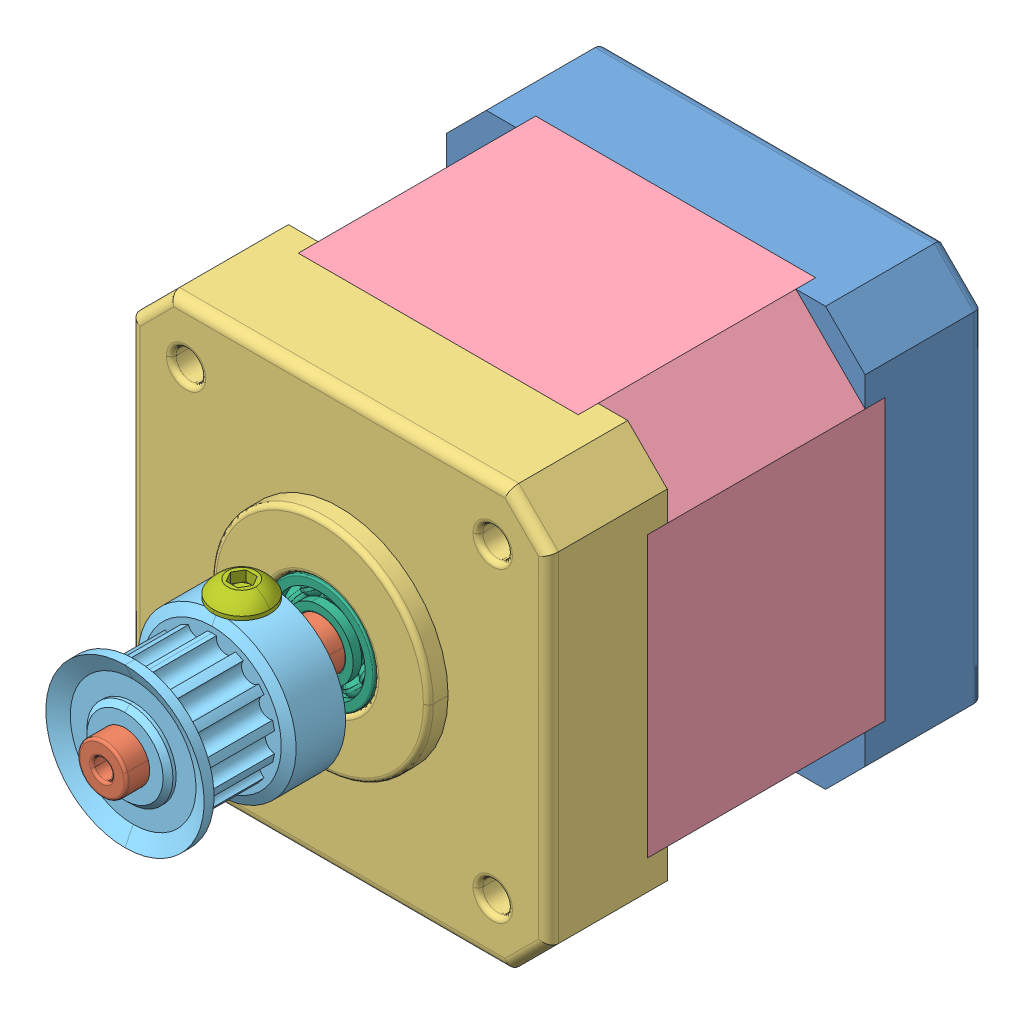
SolidWorks assembly assembly, configuration Default. Lengths in mm.
Overall size (42.3 42.3 68).
13 component instances, 8 part files, 0 mates.
Components (placement in the parent):
- assembly.STEP-1: assembly.STEP [Default] at origin size (42.3 42.3 68)
  - base.STEP-1: base.STEP [Default] at (10.8393 27.1386 29.2882) size (42.3 42.3 12)
  - axial_rod.STEP-1: axial_rod.STEP [Default] at (10.8393 27.1386 29.2882) x (0.938585 0.345048 0) z (0 0 1) size (5 5 68)
  - back_plate.STEP-1: back_plate.STEP [Default] at (10.8393 27.1386 73.2882) x (-1 0 0) z (0 0 -1) size (42.3 42.3 14)
  - body.STEP-1: body.STEP [Default] at (10.8393 27.1386 39.2882) size (42.3 42.3 24)
  - pulley.STEP-1: pulley.STEP [Default] at (10.8393 27.1386 80.1596) x (0 0 1) z (-0.000036 1 0) size (14.8 16 16)
  - instrument ball bearing_68_am_AFBMA 12.1.4.1 - 0050-11 - 10,DE,AC,10_68.STEP-1: instrument ball bearing_68_am_AFBMA 12.1.4.1 - 0050-11 - 10,DE,AC,10_68.STEP [Default] at (10.8393 27.1386 73.7882) x (0 0 1) z (0.245688 -0.969349 0) size (3 11 11)
  - instrument ball bearing_68_am_AFBMA 12.1.4.1 - 0050-11 - 10,DE,AC,10_68.STEP-2: instrument ball bearing_68_am_AFBMA 12.1.4.1 - 0050-11 - 10,DE,AC,10_68.STEP [Default] at (10.8393 27.1386 30.7882) x (0 0 1) z (-0.240367 -0.970682 0) size (3 11 11)
  - socket button head cap screw_am_B18.3.4M - 3 x 0.5 x 5 SBHCS --S.STEP-1: socket button head cap screw_am_B18.3.4M - 3 x 0.5 x 5 SBHCS --S.STEP [Default] at (10.839 36.7886 83.1596) x (0.000036 -1 0) z (0 0 1) size (6.65 5.7 5.7)
  - pan cross head_am_B18.6.7M - M3 x 0.5 x 5 Type I Cross Recessed PHMS --5S.STEP-1: pan cross head_am_B18.6.7M - M3 x 0.5 x 5 Type I Cross Recessed PHMS --5S.STEP [Default] at (26.3393 42.6386 29.8882) x (0 0 1) z (-0.840101 -0.542431 0) size (7.37 5.6 5.6)
  - pan cross head_am_B18.6.7M - M3 x 0.5 x 5 Type I Cross Recessed PHMS --5S.STEP-2: pan cross head_am_B18.6.7M - M3 x 0.5 x 5 Type I Cross Recessed PHMS --5S.STEP [Default] at (-4.6607 42.6386 29.8882) x (0 0 1) z (-1 0 0) size (7.37 5.6 5.6)
  - pan cross head_am_B18.6.7M - M3 x 0.5 x 5 Type I Cross Recessed PHMS --5S.STEP-3: pan cross head_am_B18.6.7M - M3 x 0.5 x 5 Type I Cross Recessed PHMS --5S.STEP [Default] at (-4.6607 11.6386 29.8882) x (0 0 1) z (-0.812167 -0.583425 0) size (7.37 5.6 5.6)
  - pan cross head_am_B18.6.7M - M3 x 0.5 x 5 Type I Cross Recessed PHMS --5S.STEP-4: pan cross head_am_B18.6.7M - M3 x 0.5 x 5 Type I Cross Recessed PHMS --5S.STEP [Default] at (26.3393 11.6386 29.8882) x (0 0 1) z (-0.805556 -0.592519 0) size (7.37 5.6 5.6)
